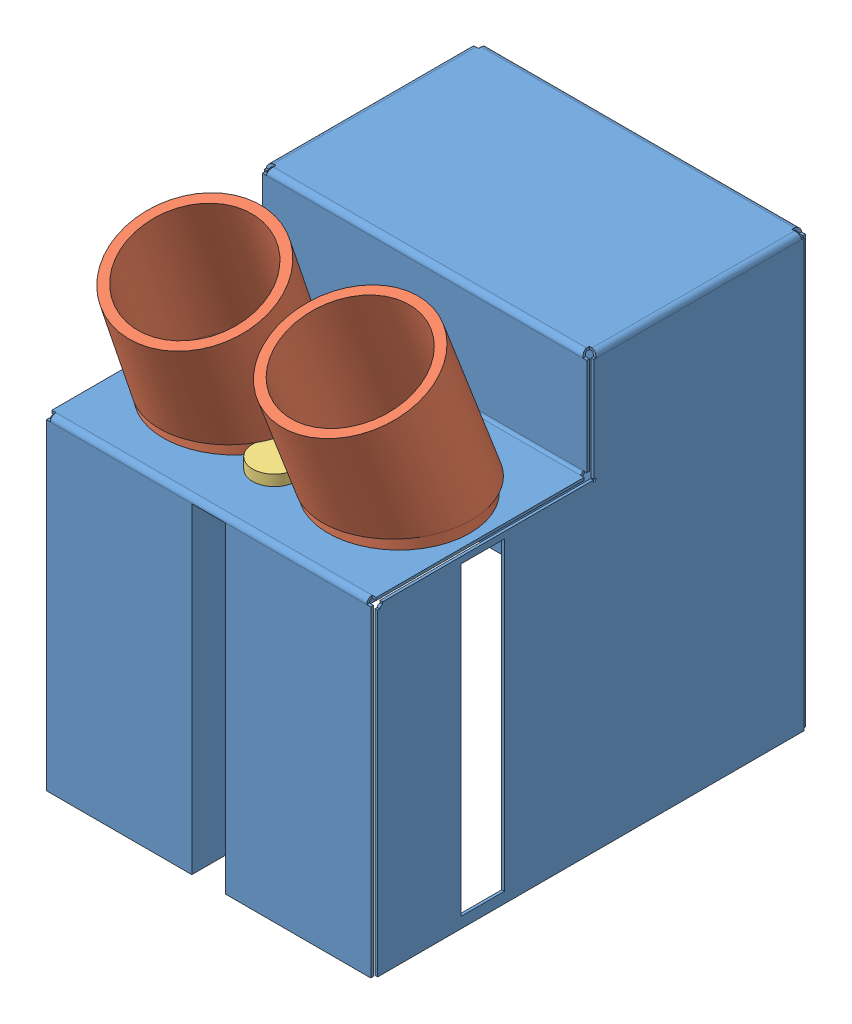
SolidWorks assembly Assem1, configuration Default. Lengths in mm.
Overall size (465.7 568.64 527.4).
4 component instances, 3 part files, 9 mates.
Components (placement in the parent):
- Bubbler-1: Bubbler [Default] at (50.9058 -97.9899 583.9033) size (387.37 508.01 511.18)
- Barrell-1: Barrell [Default] at (147.7433 298.8851 714.0783) x (-0.098966 -0.34202 0.934467) z (-0.994439 0 -0.105317) size (166.95 192.88 254)
- Barrell-2: Barrell [Default] at (-45.9317 298.8851 714.0783) x (0.098966 -0.34202 0.934467) z (-0.994439 0 0.105317) size (166.95 192.88 254)
- Gear-1: Gear [Default] at (50.9058 292.5351 763.845) x (-0.776468 0 -0.630157) z (0.630157 0 -0.776468) size (50.8 12.7 50.8)
Mates (geometry in assembly coordinates):
- Concentric1: concentric aligned: circle of Bubbler-1; cylinder of Barrell-2 through (-45.9317 286.1851 714.0783) axis (0 1 0) radius 83.4771
- Coincident18: coincident anti-aligned: plane of Bubbler-1 through (244.5808 286.1851 587.0783) normal (0 1 0); plane of Barrell-2 through (-45.9317 286.1851 714.0783) normal (0 -1 0)
- Concentric2: concentric aligned: cylinder of Bubbler-1 through (147.7433 283.0101 714.0783) axis (0 1 0) radius 72.5043; cylinder of Barrell-1 through (147.7433 286.1851 714.0783) axis (0 1 0) radius 83.4771
- Coincident19: coincident anti-aligned: plane of Bubbler-1 through (244.5808 286.1851 587.0783) normal (0 1 0); plane of Barrell-1 through (147.7433 286.1851 714.0783) normal (0 -1 0)
- Tangent1: tangent anti-aligned: cylinder of Barrell-2 through (-45.9317 286.1851 714.0783) axis (0 1 0) radius 83.4771; cylinder of Gear-1 through (50.9058 298.8851 763.845) axis (0 -1 0) radius 25.4
- Tangent2: tangent anti-aligned: cylinder of Barrell-1 through (147.7433 286.1851 714.0783) axis (0 1 0) radius 83.4771; cylinder of Gear-1 through (50.9058 298.8851 763.845) axis (0 -1 0) radius 25.4
- Coincident20: coincident anti-aligned: plane of Bubbler-1 through (244.5808 286.1851 587.0783) normal (0 1 0); plane of Gear-1 through (50.9058 286.1851 763.845) normal (0 -1 0)
- GearMate4: gear = 50.8 : 166.9542 mm: cylinder of Barrell-2 through (-45.9317 286.1851 714.0783) axis (0 1 0) radius 83.4771; cylinder of Gear-1 through (50.9058 298.8851 763.845) axis (0 -1 0) radius 25.4
- GearMate5: gear = 50.8 : 166.9542 mm: cylinder of Barrell-1 through (147.7433 286.1851 714.0783) axis (0 1 0) radius 83.4771; cylinder of Gear-1 through (50.9058 298.8851 763.845) axis (0 -1 0) radius 25.4
